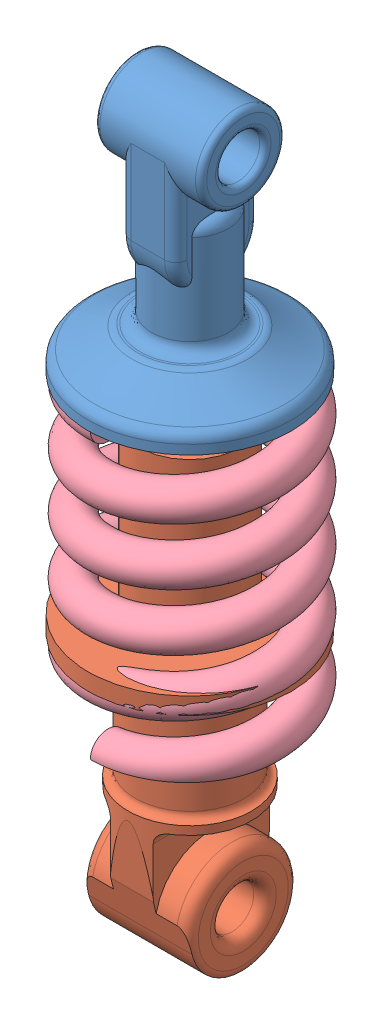
SolidWorks assembly Shock, configuration Default. Lengths in mm.
Overall size (46.33 168.53 47.49).
4 component instances, 4 part files, 11 mates.
Components (placement in the parent):
- Shock Anchor_11-1: Shock Anchor_11 [Default] at (152.5977 0 0) size (46 57.15 46)
- Shock Tube 1_11-1: Shock Tube 1_11 [Default] at (152.5977 -128.45 0) x (-1 0 0) z (0 0 1) size (46 109.21 46)
- Shock Absorber Rod_11-1: Shock Absorber Rod_11 [Default] at (152.5977 -66.839 0) x (0.425717 0 0.904857) z (-0.904857 0 0.425717) size (6.35 19.21 6.35)
- Shock Spring_11-1: Shock Spring_11 [Default] at (152.9274 -111.8466 -0.1604) size (46 72.22 47.49)
Mates (geometry in assembly coordinates):
- Concentric1: concentric: cylinder of Shock Anchor_11-1 through (158.9477 0 0) axis (-1 0 0) radius 5
- Coincident3: coincident aligned: plane of Shock Anchor_11-1 through (152.5977 0 0) normal (0 0 1)
- Concentric2: concentric aligned: circle of Shock Anchor_11-1; circle of Shock Absorber Rod_11-1
- Coincident4: coincident anti-aligned: plane of Shock Anchor_11-1 through (152.5977 -47.625 0) normal (0 -1 0); plane of Shock Absorber Rod_11-1 through (152.5977 -47.625 0) normal (0 1 0)
- Concentric3: concentric anti-aligned: cylinder of Shock Tube 1_11-1 through (152.5977 -75.1874 0) axis (0 1 0) radius 3.175; cylinder of Shock Absorber Rod_11-1 through (152.5977 -47.625 0) axis (0 -1 0) radius 3.175
- Coincident5: coincident anti-aligned: plane of Shock Anchor_11-1 through (152.5977 -47.625 0) normal (0 -1 0); plane of Shock Spring_11-1 through (152.9274 -47.625 -0.1604) normal (0 1 0)
- Lock1: lock: unknown of Shock Anchor_11-1; unknown of Shock Spring_11-1
- Parallel1: parallel anti-aligned: cylinder of Shock Anchor_11-1 through (158.9477 0 0) axis (-1 0 0) radius 5; cylinder of Shock Tube 1_11-1 through (140.5327 -147.5 0) axis (1 0 0) radius 4.9166
- Parallel4: parallel anti-aligned: line of Shock Anchor_11-1 through (0 24.13 164.6627) axis (0 0 -1); line of Shock Tube 1_11-1 through (24.13 140.5327 -147.5) axis (0 1 0)
- LimitDistance1: limit distance = 147.5 mm: line of Shock Tube 1_11-1 through (24.13 140.5327 -147.5) axis (0 1 0); line of Shock Anchor_11-1 through (0 24.13 164.6627) axis (0 0 -1)
- Distance1: distance = 147.5 mm: line of Shock Anchor_11-1 through (0 24.13 164.6627) axis (0 0 -1); line of Shock Tube 1_11-1 through (24.13 140.5327 -147.5) axis (0 1 0)
